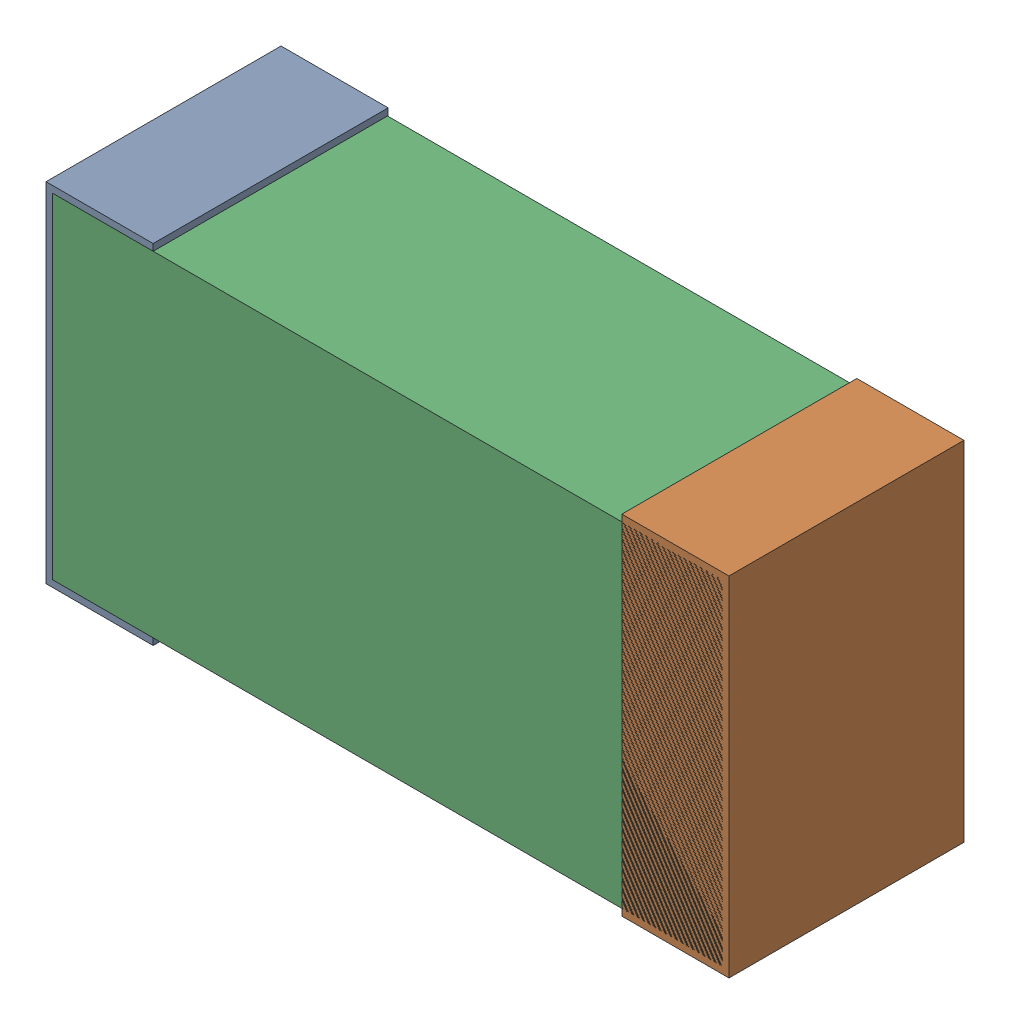
SolidWorks assembly C34, configuration Default. Lengths in mm.
Overall size (1.02 0.52 0.35).
6 component instances, 2 part files, 0 mates.
Components (placement in the parent):
- 870940480-1: 870940480 [Default] at (83.0277 32.2771 -1.9516) size (0.16 0.52 0.35)
  - Extruded-1: Extruded [Default] at origin size (0.16 0.52 0.35)
- 870940480-2: 870940480 [Default] at (83.8877 32.2771 -1.9516) size (0.16 0.52 0.35)
  - Extruded-1: Extruded [Default] at origin size (0.16 0.52 0.35)
- 870940640-1: 870940640 [Default] at (83.4577 32.2771 -1.9506) size (1 0.5 0.35)
  - Extruded_2-1: Extruded_2 [Default] at origin size (1 0.5 0.35)
